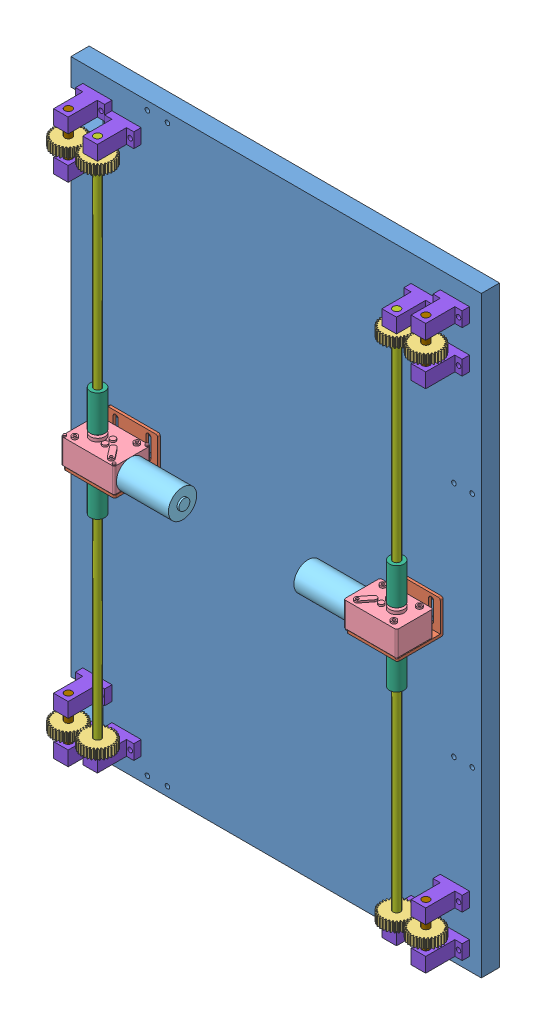
SolidWorks assembly 装配体5, configuration 默认. Lengths in mm.
Overall size (450 650 75.63).
39 component instances, 9 part files, 0 mates.
Components (placement in the parent):
- 座板5-1: 座板5 [默认] at (-85.6176 9.4134 640) size (450 650 20)
- 角度电机支架-1: 角度电机支架 [默认] at (41.3824 -11.5866 660) x (0 1 0) z (1 0 0) size (37 50 56)
- spur gear_gb-1: spur gear_gb [GB - Spur gear 1M 32T 20PA 10FW ---S32A75H50L8.0N] at (110.3824 -265.5866 691.77) x (0 -1 0) z (-0.637461 0 0.770483) size (10 33.89 33.89)
- spur gear_gb-2: spur gear_gb [GB - Spur gear 1M 32T 20PA 10FW ---S32A75H50L8.0N] at (78.3824 -265.5866 691.7667) x (0 -1 0) z (0 0 1) size (10 33.89 33.89)
- 角电机减速机1-1: 角电机减速机1 [默认] at (69.2824 -6.5866 691.7667) x (1 0 0) z (0 -1 0) size (58.2 40 66)
- 角度电机-1: 角度电机 [默认] at (40.1824 4.9134 693.7667) x (-1 0 0) z (0 -0.900769 -0.434299) size (74 31 31)
- 联轴器2-1: 联轴器2 [默认] at (78.3824 -33.0866 691.7667) x (-0.028487 0 0.999594) z (0 1 0) size (16 16 40)
- 轴-1: 轴 [默认] at (78.3824 -291.5866 691.7667) x (0.269951 0 -0.962874) z (0 1 0) size (8 8 251.5)
- 支柱1-1: 支柱1 [默认] at (78.3824 -275.5866 660) x (1 0 0) z (0 -1 0) size (32 40 16)
- 支柱1-2: 支柱1 [默认] at (110.3824 -285.5866 660) x (1 0 0) z (0 -1 0) size (32 40 16)
- 支柱1-3: 支柱1 [默认] at (110.3824 -239.5866 660) x (1 0 0) z (0 -1 0) size (32 40 16)
- 轴2-1: 轴2 [默认] at (110.3824 -239.5866 691.77) x (1 0 0) z (0 -1 0) size (8 8 62)
- 联轴器2-5: 联轴器2 [默认] at (78.3824 46.9134 691.7667) x (-0.028487 0 0.999594) z (0 1 0) size (16 16 40)
- 轴-5: 轴 [默认] at (78.3824 53.9134 691.7667) x (0.269951 0 -0.962874) z (0 1 0) size (8 8 251.5)
- spur gear_gb-9: spur gear_gb [GB - Spur gear 1M 32T 20PA 10FW ---S32A75H50L8.0N] at (78.3824 279.4134 691.7667) x (0 1 0) z (0 0 -1) size (10 33.89 33.89)
- 支柱1-13: 支柱1 [默认] at (78.3824 305.4134 660) x (1 0 0) z (0 -1 0) size (32 40 16)
- 支柱1-14: 支柱1 [默认] at (110.3824 315.4134 660) x (1 0 0) z (0 -1 0) size (32 40 16)
- 轴2-5: 轴2 [默认] at (110.3824 315.4134 691.77) x (1 0 0) z (0 -1 0) size (8 8 62)
- spur gear_gb-10: spur gear_gb [GB - Spur gear 1M 32T 20PA 10FW ---S32A75H50L8.0N] at (110.3824 279.4134 691.77) x (0 1 0) z (0.637461 0 -0.770483) size (10 33.89 33.89)
- 支柱1-15: 支柱1 [默认] at (110.3824 269.4134 660) x (1 0 0) z (0 -1 0) size (32 40 16)
- 支柱1-16: 支柱1 [默认] at (-249.6176 -291.5866 660) x (-1 0 0) z (0 1 0) size (32 40 16)
- 轴-6: 轴 [默认] at (-249.6176 -40.0866 691.7667) x (-0.269951 0 -0.962874) z (0 -1 0) size (8 8 251.5)
- 联轴器2-6: 联轴器2 [默认] at (-249.6176 -33.0866 691.7667) x (0.028487 0 0.999594) z (0 -1 0) size (16 16 40)
- 角度电机支架-3: 角度电机支架 [默认] at (-268.6176 -11.5866 660) x (0 1 0) z (1 0 0) size (37 50 56)
- 角电机减速机1-3: 角电机减速机1 [默认] at (-240.5176 20.4134 691.7667) x (-1 0 0) z (0 1 0) size (58.2 40 66)
- 角度电机-3: 角度电机 [默认] at (-211.4176 4.9134 693.7667) x (1 0 0) z (0 0.900769 0.434299) size (74 31 31)
- spur gear_gb-11: spur gear_gb [GB - Spur gear 1M 32T 20PA 10FW ---S32A75H50L8.0N] at (-249.6176 -265.5866 691.7667) x (0 -1 0) z (0 0 -1) size (10 33.89 33.89)
- 支柱1-17: 支柱1 [默认] at (-281.6176 -255.5866 660) x (-1 0 0) z (0 1 0) size (32 40 16)
- 支柱1-18: 支柱1 [默认] at (-281.6176 -301.5866 660) x (-1 0 0) z (0 1 0) size (32 40 16)
- 轴2-6: 轴2 [默认] at (-281.6176 -301.5866 691.77) x (-1 0 0) z (0 1 0) size (8 8 62)
- 联轴器2-7: 联轴器2 [默认] at (-249.6176 46.9134 691.7667) x (0.028487 0 0.999594) z (0 -1 0) size (16 16 40)
- 轴-7: 轴 [默认] at (-249.6176 305.4134 691.7667) x (-0.269951 0 -0.962874) z (0 -1 0) size (8 8 251.5)
- spur gear_gb-12: spur gear_gb [GB - Spur gear 1M 32T 20PA 10FW ---S32A75H50L8.0N] at (-249.6176 279.4134 691.7667) x (0 1 0) z (0 0 1) size (10 33.89 33.89)
- 支柱1-19: 支柱1 [默认] at (-249.6176 289.4134 660) x (-1 0 0) z (0 1 0) size (32 40 16)
- 支柱1-20: 支柱1 [默认] at (-281.6176 299.4134 660) x (-1 0 0) z (0 1 0) size (32 40 16)
- 支柱1-21: 支柱1 [默认] at (-281.6176 253.4134 660) x (-1 0 0) z (0 1 0) size (32 40 16)
- 轴2-7: 轴2 [默认] at (-281.6176 253.4134 691.77) x (-1 0 0) z (0 1 0) size (8 8 62)
- spur gear_gb-13: spur gear_gb [GB - Spur gear 1M 32T 20PA 10FW ---S32A75H50L8.0N] at (-281.6176 -275.5866 691.77) x (0 1 0) z (0.089959 0 0.995946) size (10 33.89 33.89)
- spur gear_gb-15: spur gear_gb [GB - Spur gear 1M 32T 20PA 10FW ---S32A75H50L8.0N] at (-281.6176 289.4134 691.77) x (0 -1 0) z (-0.089959 0 -0.995946) size (10 33.89 33.89)
